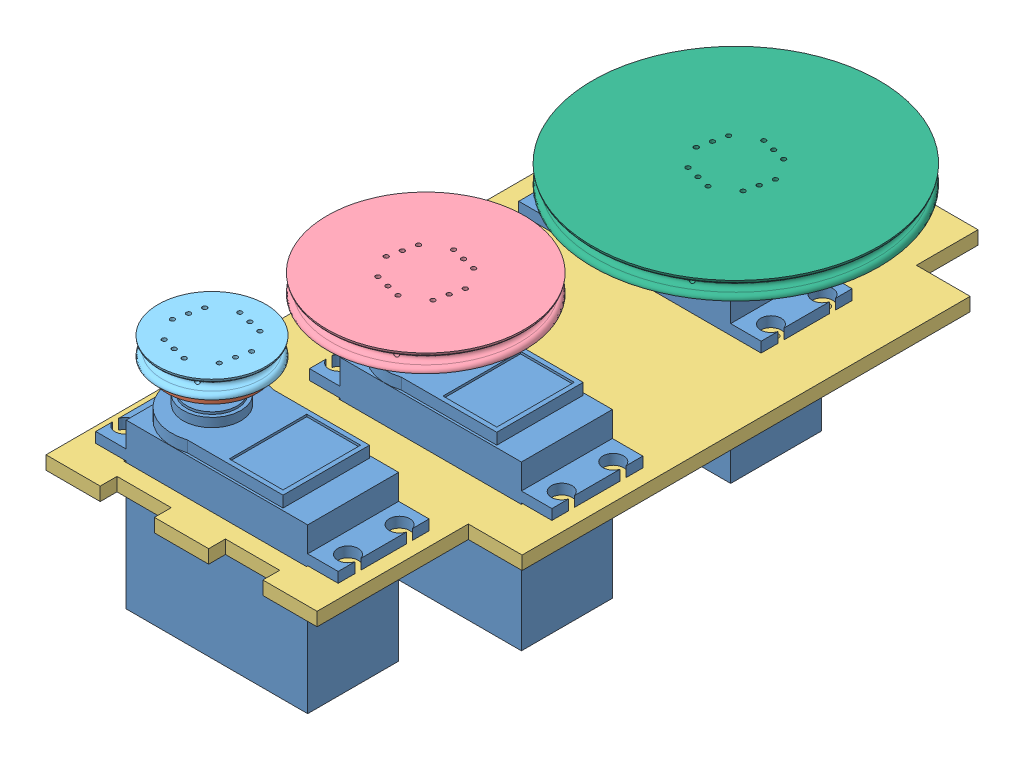
SolidWorks assembly ServoSet, configuration Default. Lengths in mm.
Overall size (82.84 52.3 148.09).
13 component instances, 6 part files, 18 mates.
Components (placement in the parent):
- 55gServoAndAttachment-1: 55gServoAndAttachment [Default] at (-42.4416 98.8668 240.9659) x (0 0 -1) z (1 0 0) size (24.11 48.3 54.1)
  - 55gServoMotor-1: 55gServoMotor [Default] at (29.3026 10.0421 49.0781) size (20.3 45.5 54.1)
  - CircularAttachment-1: CircularAttachment [Default] at (29.3026 56.1421 60.3281) x (0.973354 0 0.229307) z (-0.229307 0 0.973354) size (20.05 5.6 20.05)
- ServoHolderDirect-2: ServoHolderDirect [Default] at (3.7865 137.5089 247.5133) x (-1 0 0) z (0 0 1) size (72.5 3 147.5)
- 55gServoAndAttachment-4: 55gServoAndAttachment [Default] at (64.7146 98.8668 238.0606) x (0 0 1) z (-1 0 0) size (24.11 48.3 54.1)
  - 55gServoMotor-1: 55gServoMotor [Default] at (29.3026 10.0421 49.0781) size (20.3 45.5 54.1)
  - CircularAttachment-1: CircularAttachment [Default] at (29.3026 56.1421 60.3281) x (0.973354 0 0.229307) z (-0.229307 0 0.973354) size (20.05 5.6 20.05)
- 55gServoAndAttachment-5: 55gServoAndAttachment [Default] at (53.0146 98.8668 274.0606) x (0 0 1) z (-1 0 0) size (24.11 48.3 54.1)
  - 55gServoMotor-1: 55gServoMotor [Default] at (29.3026 10.0421 49.0781) size (20.3 45.5 54.1)
  - CircularAttachment-1: CircularAttachment [Default] at (29.3026 56.1421 60.3281) x (0.973354 0 0.229307) z (-0.229307 0 0.973354) size (20.05 5.6 20.05)
- MotorTransmissionMedium-1: MotorTransmissionMedium [Default] at (4.3865 154.2089 267.3633) x (0.973354 0 0.229307) z (0.229307 0 -0.973354) size (44 4 44)
- MotorTransmissionSmall-1: MotorTransmissionSmall [Default] at (-7.3135 154.2089 303.3633) x (0.973354 0 0.229307) z (0.229307 0 -0.973354) size (24 4 24)
- MotorTransmissionLarge-1: MotorTransmissionLarge [Default] at (17.8865 154.2089 211.6633) x (-0.973354 0 -0.229307) z (-0.229307 0 0.973354) size (64 4 64)
Mates (geometry in assembly coordinates):
- Coincident16: coincident anti-aligned: plane of Motor_and_attachmentDirect-4/ServoAttachmentDirect-1 through (4.3865 157.2089 267.3633) normal (0 1 0); plane of MotorTransmissionMedium-1 through (4.3865 157.2089 267.3633) normal (0 -1 0)
- Coincident17: coincident anti-aligned: plane of Motor_and_attachmentDirect-5/ServoAttachmentDirect-1 through (-7.3135 157.2089 303.3633) normal (0 1 0); plane of MotorTransmissionSmall-1 through (-7.3135 157.2089 303.3633) normal (0 -1 0)
- Coincident18: coincident anti-aligned: plane of Motor_and_attachmentDirect-1/ServoAttachmentDirect-1 through (17.8865 157.2089 211.6633) normal (0 1 0); plane of MotorTransmissionLarge-1 through (17.8865 157.2089 211.6633) normal (0 -1 0)
- Concentric38: concentric aligned: cylinder of Motor_and_attachmentDirect-5/ServoAttachmentDirect-1 through (-11.8445 157.2089 309.5132) axis (0 -1 0) radius 0.5; cylinder of MotorTransmissionSmall-1 through (-11.8445 161.2089 309.5132) axis (0 -1 0) radius 0.5
- Concentric39: concentric aligned: cylinder of Motor_and_attachmentDirect-5/ServoAttachmentDirect-1 through (-6.0043 157.2089 310.889) axis (0 -1 0) radius 0.5; cylinder of MotorTransmissionSmall-1 through (-6.0043 161.2089 310.889) axis (0 -1 0) radius 0.5
- Concentric40: concentric aligned: cylinder of Motor_and_attachmentDirect-1/ServoAttachmentDirect-1 through (16.5773 157.2089 204.1376) axis (0 -1 0) radius 0.5; cylinder of MotorTransmissionLarge-1 through (16.5773 161.2089 204.1376) axis (0 -1 0) radius 0.5
- Parallel1: parallel aligned: cylinder of MotorTransmissionLarge-1 through (22.4174 161.2089 205.5134) axis (0 -1 0) radius 0.5; cylinder of Motor_and_attachmentDirect-1/ServoAttachmentDirect-1 through (22.4174 157.2089 205.5134) axis (0 -1 0) radius 0.5
- Concentric41: concentric aligned: cylinder of Motor_and_attachmentDirect-4/ServoAttachmentDirect-1 through (-3.1392 157.2089 268.6725) axis (0 -1 0) radius 0.5; cylinder of MotorTransmissionMedium-1 through (-3.1392 161.2089 268.6725) axis (0 -1 0) radius 0.5
- Concentric42: concentric aligned: cylinder of Motor_and_attachmentDirect-4/ServoAttachmentDirect-1 through (-1.7634 157.2089 262.8323) axis (0 -1 0) radius 0.5; cylinder of MotorTransmissionMedium-1 through (-1.7634 161.2089 262.8323) axis (0 -1 0) radius 0.5
- Coincident51: coincident anti-aligned: plane of 55gServoAndAttachment-1/55gServoMotor-1 through (26.8865 145.4089 221.8133) normal (0 0 1); plane of ServoHolderDirect-2 through (3.7865 134.5089 221.8133) normal (0 0 -1)
- Coincident52: coincident anti-aligned: plane of 55gServoAndAttachment-1/55gServoMotor-1 through (-13.6135 145.4089 221.8133) normal (-1 0 0); plane of ServoHolderDirect-2 through (-13.6135 134.5089 247.5133) normal (1 0 0)
- Coincident54: coincident anti-aligned: plane of 55gServoAndAttachment-1/55gServoMotor-1 through (-20.4135 137.5089 201.5133) normal (0 -1 0); plane of ServoHolderDirect-2 through (3.7865 137.5089 247.5133) normal (0 1 0)
- Coincident55: coincident anti-aligned: plane of ServoHolderDirect-2 through (3.7865 134.5089 257.2133) normal (0 0 1); plane of 55gServoAndAttachment-4/55gServoMotor-1 through (-4.6135 145.4089 257.2133) normal (0 0 -1)
- Coincident56: coincident anti-aligned: plane of ServoHolderDirect-2 through (-4.6135 134.5089 247.5133) normal (1 0 0); plane of 55gServoAndAttachment-4/55gServoMotor-1 through (-4.6135 145.4089 257.2133) normal (-1 0 0)
- Coincident57: coincident anti-aligned: plane of ServoHolderDirect-2 through (3.7865 137.5089 247.5133) normal (0 1 0); plane of 55gServoAndAttachment-4/55gServoMotor-1 through (-11.4135 137.5089 277.5133) normal (0 -1 0)
- Coincident58: coincident anti-aligned: plane of ServoHolderDirect-2 through (3.7865 134.5089 293.2133) normal (0 0 1); plane of 55gServoAndAttachment-5/55gServoMotor-1 through (-16.3135 145.4089 293.2133) normal (0 0 -1)
- Coincident59: coincident anti-aligned: plane of ServoHolderDirect-2 through (24.1865 134.5089 247.5133) normal (-1 0 0); plane of 55gServoAndAttachment-5/55gServoMotor-1 through (24.1865 145.4089 293.2133) normal (1 0 0)
- Coincident60: coincident anti-aligned: plane of ServoHolderDirect-2 through (3.7865 137.5089 247.5133) normal (0 1 0); plane of 55gServoAndAttachment-5/55gServoMotor-1 through (-23.1135 137.5089 313.5133) normal (0 -1 0)
